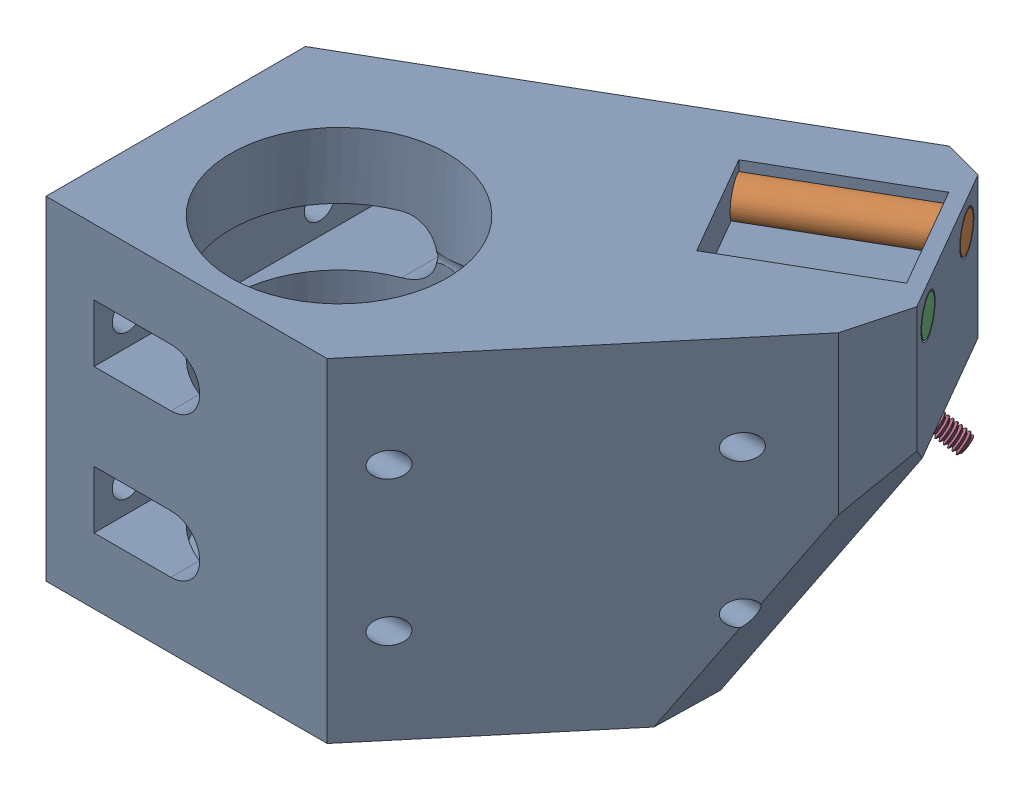
SolidWorks assembly left_coupling_side_plate_with_inserts, configuration Default. Lengths in mm.
Overall size (55.27 34.7 51.53).
4 component instances, 3 part files, 0 mates.
Components (placement in the parent):
- bed_coupling_side_plate_Front Left Bed Coupling Lift-1: bed_coupling_side_plate_Front Left Bed Coupling Lift [Default] at (-41.929 327.9642 434.2083) size (55.27 34.7 51.53)
- dowel_pin_4mm_d_20mm_l_91585A457_91585A457-1: dowel_pin_4mm_d_20mm_l_91585A457_91585A457 [Default] at (-2.4191 324.9642 405.0279) x (0.866025 0 -0.5) z (0.419287 -0.544787 0.726227) size (20 4 4)
- dowel_pin_4mm_d_20mm_l_91585A457_91585A457-2: dowel_pin_4mm_d_20mm_l_91585A457_91585A457 [Default] at (3.0969 324.9642 414.582) x (0.866025 0 -0.5) z (-0.349983 -0.714175 -0.606189) size (20 4 4)
- m2_set_screw_6mm_92015A093_92015A093-1: m2_set_screw_6mm_92015A093_92015A093 [Default] at (8.2644 311.4167 405.2292) x (-0.623704 -0.240264 -0.743819) z (0.709406 -0.573576 -0.409576) size (2.02 2.05 6.05)
